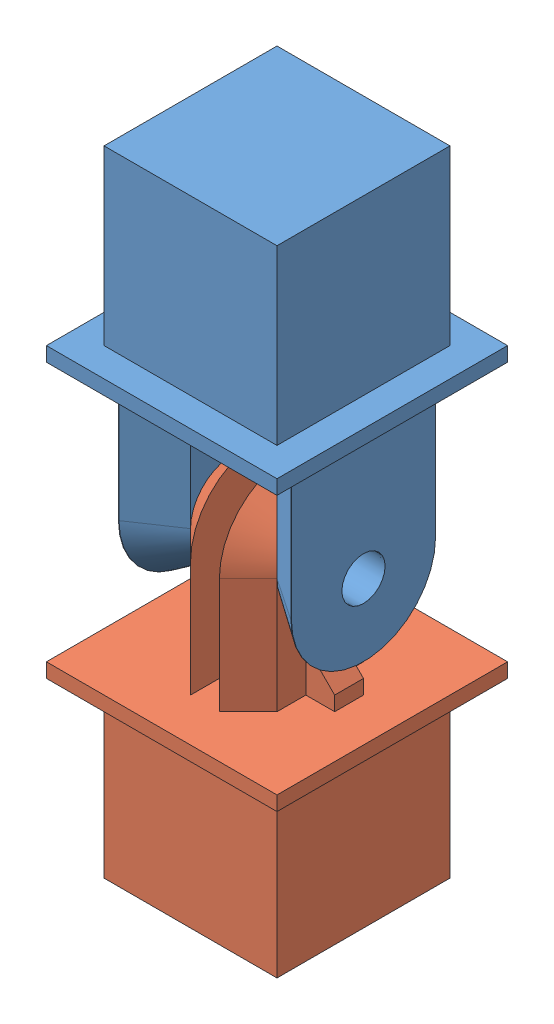
SolidWorks assembly MH_Hand1, configuration Default. Lengths in mm.
Overall size (8 22 8).
2 component instances, 2 part files, 6 mates.
Components (placement in the parent):
- Part47^MH_Hand1-1: Part47^MH_Hand1 [Default] at origin size (8 14 8) (virtual)
- Part48^MH_Hand1-1: Part48^MH_Hand1 [Default] at (0 -15.9999 -0.0001) x (1 0 0) z (0 0.000018 -1) size (8 13 8) (virtual)
Mates (geometry in assembly coordinates):
- InPlace1: in place: plane of Part47^MH_Hand1-1 through (0 0 0) normal (0 0 1); moOrthogonalPlaneRef_w of Part47^MH_Hand1-1 through (0 0 0) normal (0 1 0); plane of Part47^MH_Hand1-1 through (0 0 0) normal (1 0 0); unknown of Part47^MH_Hand1-1
- Coincident1: coincident: plane of Part47^MH_Hand1-1; plane of assembly
- Coincident2: coincident: plane of Part47^MH_Hand1-1 through (0 0 0) normal (0 1 0); moOrthogonalPlaneRef_w of assembly
- Coincident3: coincident: plane of Part47^MH_Hand1-1 through (0 0 0) normal (1 0 0); moOrthogonalPlaneRef_w of assembly
- Concentric1: concentric: cylinder of Part47^MH_Hand1-1 through (-3.5 -8.5 3) axis (1 0 0) radius 0.75; cylinder of Part48^MH_Hand1-1 through (-2.5 -8.5 3) axis (1 0 0) radius 0.75
- Coincident7: coincident: plane of Part47^MH_Hand1-1 through (1.5 -8.5 3) normal (-1 0 0); plane of Part48^MH_Hand1-1 through (1.5 -8.5 3) normal (1 0 0)
